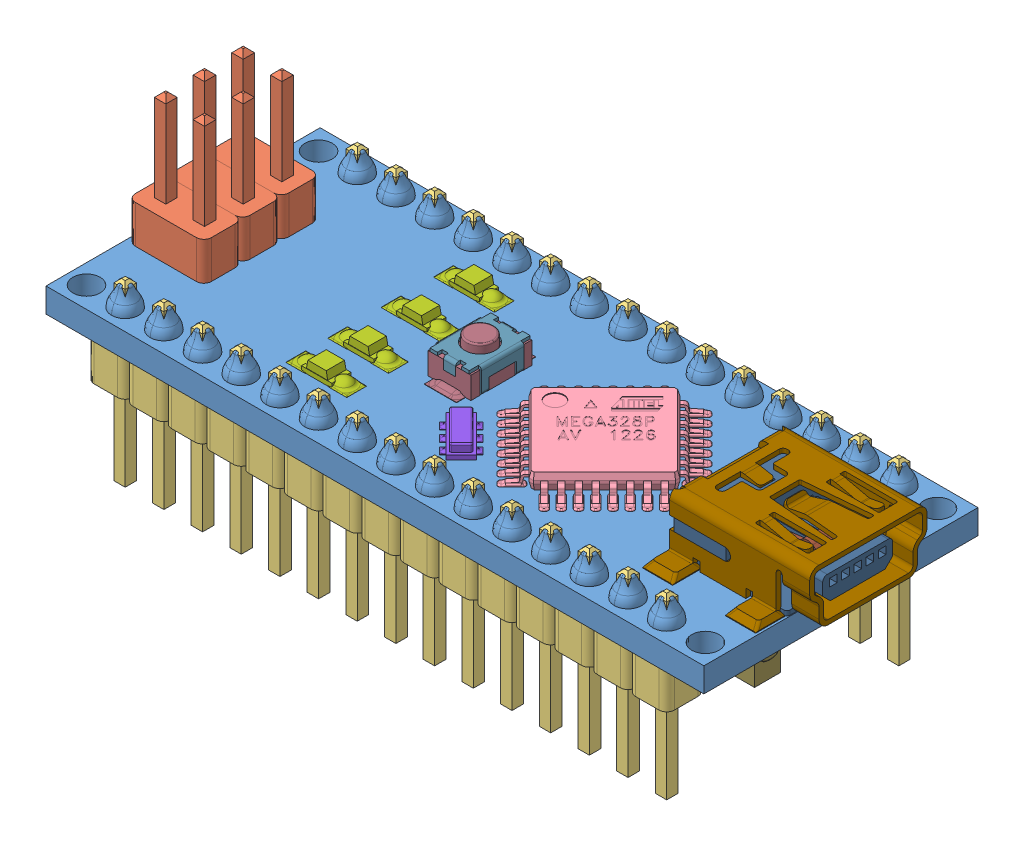
SolidWorks assembly arduino nano, configuration Défaut. Lengths in mm.
Overall size (45 18.6 18).
33 component instances, 18 part files, 0 mates.
Components (placement in the parent):
- nano-board-1: nano-board [Défaut] at origin size (43.2 4.6 18)
- 2pin_header__02-1: 2pin_header__02 [Défaut] at (-1.143 1.6 -7.62) size (5 11.75 2.54)
- 2pin_header__02-2: 2pin_header__02 [Défaut] at (-1.143 1.6 -5.08) size (5 11.75 2.54)
- 2pin_header__02-3: 2pin_header__02 [Défaut] at (-1.143 1.6 -10.16) size (5 11.75 2.54)
- 15pin_header__-1: 15pin_header__ [Défaut] x (0 0 1) z (1 0 0) size (2.54 11.75 38.1)
- 15pin_header__-2: 15pin_header__ [Défaut] at (0 0 -15.24) x (0 0 1) z (1 0 0) size (2.54 11.75 38.1)
- atmega328-1: atmega328 [Défaut] at (23.85 1.75 -7.62) x (-0.707107 0 0.707107) z (-0.707107 0 -0.707107) size (10 1.11 10)
- ftdi FT232rl-1: ftdi FT232rl [Défaut] at (29.05 0 -7.67) x (0 0 -1) z (-1 0 0) size (9.25 1.9 10.2)
- smt_resistor222-1: smt_resistor222 [Défaut] at (21.86 0 -5.8) x (0 0 -1) z (-1 0 0) size (1.7 0.6 3.8)
- smt_resistor222-2: smt_resistor222 [Défaut] at (21.86 0 -9) x (0 0 -1) z (-1 0 0) size (1.7 0.6 3.8)
- smt_resistor222-3: smt_resistor222 [Défaut] at (36.75 0 -7.6) x (0 0 -1) z (-1 0 0) size (1.7 0.6 3.8)
- smt_resistor222-4: smt_resistor222 [Défaut] at (36.75 0 -12) x (0 0 -1) z (-1 0 0) size (1.7 0.6 3.8)
- smt_resistor222-5: smt_resistor222 [Défaut] at (8.2 0 -2.6) x (0 0 -1) z (-1 0 0) size (1.7 0.6 3.8)
- led-1: led [Défaut] at (10.4 1.6 -2.8) size (4 0.9 1.55)
- led-2: led [Défaut] at (10.4 1.6 -5.55) size (4 0.9 1.55)
- led-3: led [Défaut] at (10.4 1.6 -12.5) size (4 0.9 1.55)
- led-4: led [Défaut] at (10.4 1.6 -9.05) size (4 0.9 1.55)
- 16mhz crystal - measured-1: 16mhz crystal - measured [Défaut] at (18.5113 1.6 -3.5541) x (0.707107 0 0.707107) z (-0.707107 0 0.707107) size (3.4 0.8 2)
- MINIUSBSHELL-1: MINIUSBSHELL [Défaut] at (38.98 1.65 -7.62) x (0 0 1) z (-1 0 0) size (10.9 3.85 9.41)
- MINIUSBCORE-1: MINIUSBCORE [Défaut] at (32.28 1.65 -7.62) x (0 0 -1) z (1 0 0) size (7.7 4.5 8.2)
- MINI USB CONTACT-1: MINI USB CONTACT [Défaut] at (33.28 1.65 -9.22) x (0 0 -1) z (1 0 0) size (0.53 2.55 9.41)
- MINI USB CONTACT-2: MINI USB CONTACT [Défaut] at (33.28 1.65 -8.42) x (0 0 -1) z (1 0 0) size (0.53 2.55 9.41)
- MINI USB CONTACT-3: MINI USB CONTACT [Défaut] at (33.28 1.65 -7.62) x (0 0 -1) z (1 0 0) size (0.53 2.55 9.41)
- MINI USB CONTACT-4: MINI USB CONTACT [Défaut] at (33.28 1.65 -6.82) x (0 0 -1) z (1 0 0) size (0.53 2.55 9.41)
- MINI USB CONTACT-5: MINI USB CONTACT [Défaut] at (33.28 1.65 -6.02) x (0 0 -1) z (1 0 0) size (0.53 2.55 9.41)
- cap106C-1: cap106C [Défaut] at (37.2 0 -3.3) x (0 0 1) z (1 0 0) size (1.7 1.81 4)
- cap106C-2: cap106C [Défaut] at (7.9 0 -5.6) x (0 0 -1) z (-1 0 0) size (1.7 1.81 4)
- reset core-1: reset core [Défaut] at (15.25 1.6 -8.05) x (0 0 -1) z (1 0 0) size (5.2 2.15 2.8)
- reset shell-1: reset shell [Défaut] at (15.25 3.25 -8.05) size (3 1.65 4)
- nano - reg-1: nano - reg [Défaut] at (6.1 0 -10.16) x (0 0 -1) z (-1 0 0) size (6.5 1.69 8.3)
- NANO DIODE-1: NANO DIODE [Défaut] at (11.43 0 -4.2) x (0 0 1) z (1 0 0) size (4.92 1.38 1.7)
- 189 RESISTOR PACK-1: 189 RESISTOR PACK [Défaut] at (15.75 0 -10.85) x (0 0 1) z (1 0 0) size (3.2 0.51 3)
- 102 RESISTOR PACK-1: 102 RESISTOR PACK [Défaut] at (15.75 0 -5.2) x (0 0 1) z (1 0 0) size (3.2 0.51 3)
